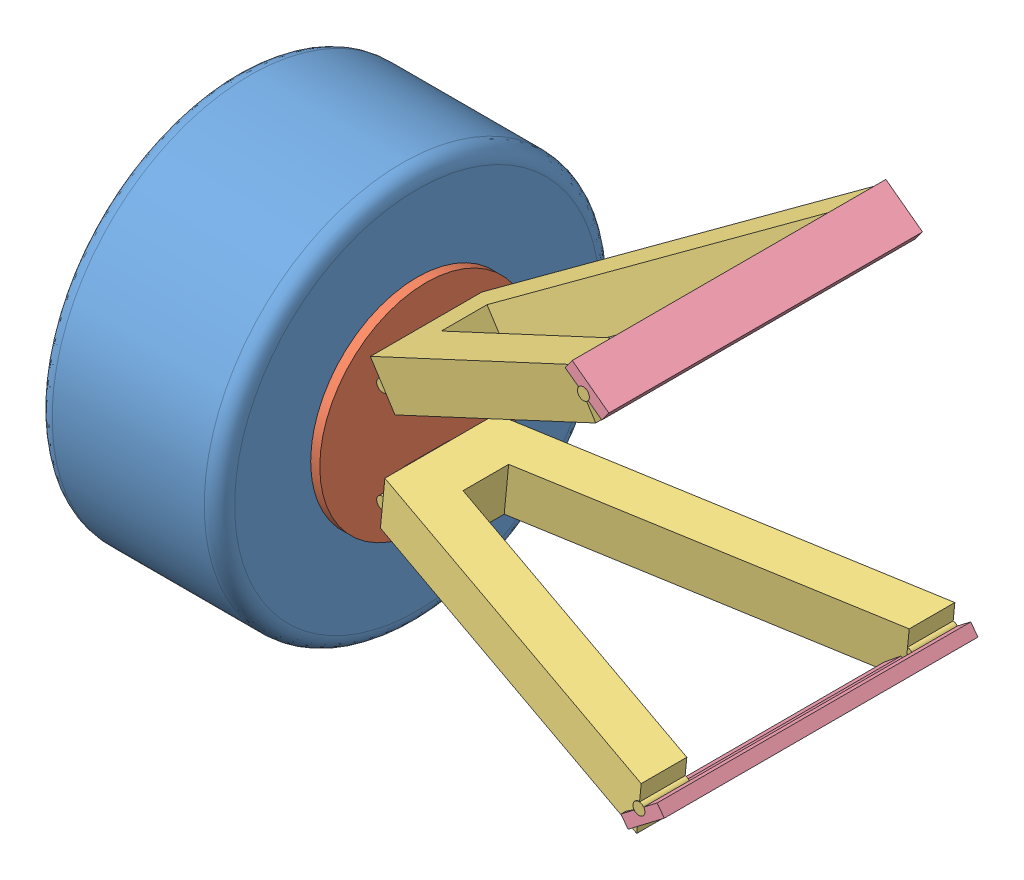
SolidWorks assembly A-Arm Visual, configuration Default. Lengths in mm.
Overall size (489.77 389.48 330.2).
6 component instances, 4 part files, 10 mates.
Components (placement in the parent):
- Front Tire-1: Front Tire [Default] at (57.0601 188.4595 237.2097) size (152.4 330.2 330.2)
- Wheel Hub-1: Wheel Hub [Default] at (217.0601 188.4595 237.2097) x (0 0 1) z (-1 0 0) size (177.8 177.8 93.8)
- A arm-1: A arm [Default] at (237.3783 214.9458 106.2597) x (0 0 1) z (-0.840614 -0.541635 0) size (261.9 38.1 310)
- A arm-2: A arm [Default] at (228.9199 164.9185 368.1597) x (0 0 -1) z (-0.995223 0.097625 0) size (261.9 38.1 310)
- A-Arm Frame Hinge-1: A-Arm Frame Hinge [Default] at (484.7533 401.8147 286.1823) x (0 0 -1) z (-0.802819 0.596223 0) size (261.9 10 38.1)
- A-Arm Frame Hinge-2: A-Arm Frame Hinge [Default] at (531.2549 108.3867 188.2371) x (0 0 1) z (-0.794238 -0.607607 0) size (261.9 10 38.1)
Mates (geometry in assembly coordinates):
- Concentric1: concentric anti-aligned: cylinder of Front Tire-1 through (209.4601 188.4595 237.2097) axis (-1 0 0) radius 88.9; cylinder of Wheel Hub-1 through (133.2601 188.4595 237.2097) axis (1 0 0) radius 88.9
- Coincident1: coincident anti-aligned: plane of Front Tire-1 through (133.2601 188.4595 237.2097) normal (1 0 0); plane of Wheel Hub-1 through (133.2601 188.4595 237.2097) normal (-1 0 0)
- Concentric2: concentric aligned: cylinder of Wheel Hub-1 through (227.0601 230.9595 148.3097) axis (0 0 1) radius 2.5; cylinder of A arm-1 through (227.0601 230.9595 190.7958) axis (0 0 1) radius 5
- Coincident2: coincident: plane of Wheel Hub-1 through (227.0601 238.4595 218.1597) normal (0 0 -1); point of A arm-1
- Concentric3: concentric anti-aligned: cylinder of Wheel Hub-1 through (227.0601 145.9595 211.0887) axis (0 0 1) radius 2.5; cylinder of A arm-2 through (227.0601 145.9595 283.6236) axis (0 0 -1) radius 5
- Coincident3: coincident: plane of Wheel Hub-1 through (227.0601 138.4595 218.1597) normal (0 0 -1); point of A arm-2
- Concentric4: concentric anti-aligned: cylinder of A arm-1 through (479.2443 393.45 106.2597) axis (0 0 1) radius 5; cylinder of A-Arm Frame Hinge-1 through (479.2443 393.45 382.3019) axis (0 0 -1) radius 5
- Coincident4: coincident aligned: plane of A arm-1 through (479.2443 393.45 106.2597) normal (0 0 -1); plane of A-Arm Frame Hinge-1 through (494.538 382.0919 106.2597) normal (0 0 -1)
- Concentric5: concentric aligned: cylinder of A arm-2 through (525.6271 116.672 106.2597) axis (0 0 1) radius 5; cylinder of A-Arm Frame Hinge-2 through (525.6271 116.672 92.1176) axis (0 0 1) radius 5
- Coincident5: coincident aligned: plane of A arm-2 through (525.6271 116.672 106.2597) normal (0 0 -1); plane of A-Arm Frame Hinge-2 through (540.7573 128.2469 106.2597) normal (0 0 -1)
